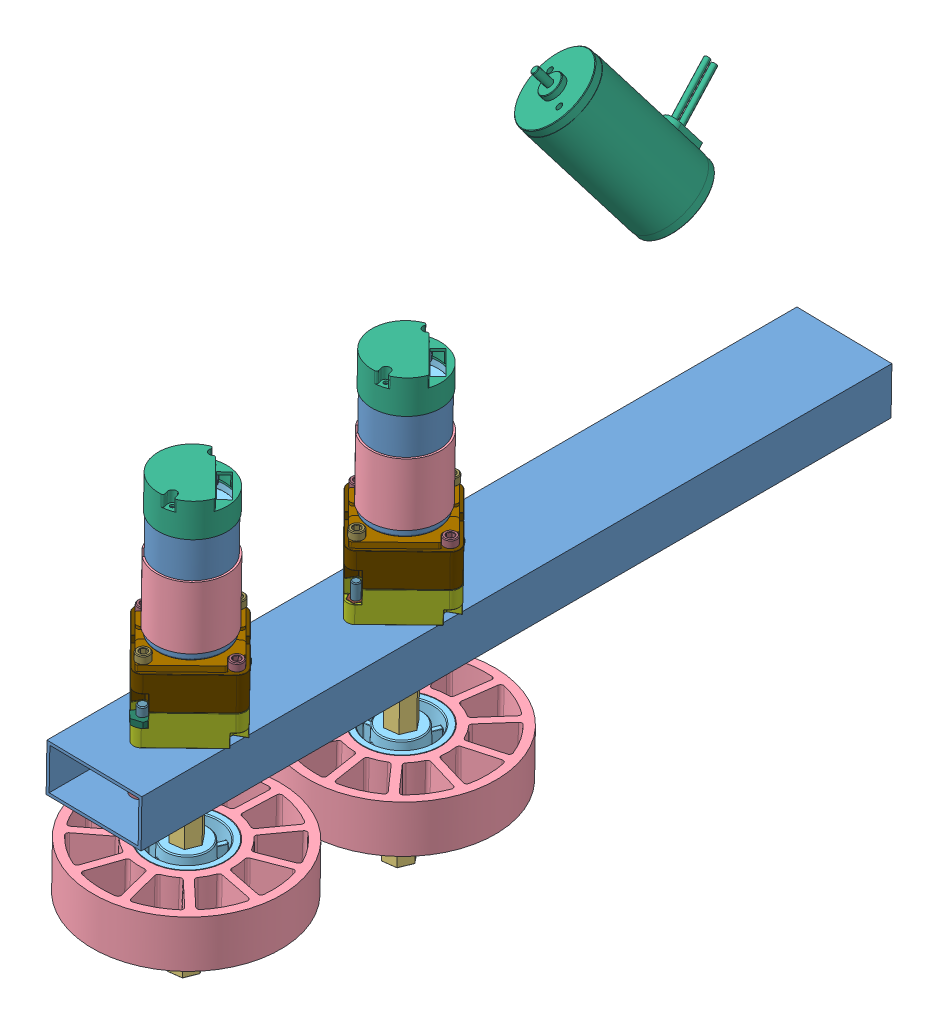
SolidWorks assembly intake final, configuration Default. Lengths in mm.
Overall size (289.95 238.09 525.75).
113 component instances, 33 part files, 37 mates.
Components (placement in the parent):
- 1X2 by 15 inch thin-1: 1X2 by 15 inch thin [Default] at (-67.4663 99.9227 151.2004) x (0.999855 -0.01704 -0.000167) z (0.000167 0.000026 1) size (50.8 25.4 401.32)
- Hex Bearing .5 in internal-4: Hex Bearing .5 in internal [Default] at (-41.9351 105.0953 387.416) x (-0.999854 0.01704 0.001214) z (0.001214 0.000008 0.999999) size (31.12 7.94 31.12)
- Hex shaft 0.5-2: Hex shaft 0.5 [Default] at (-43.6631 0.2077 387.3715) x (-0.623949 0.010611 -0.781393) z (0.01704 0.999855 -0.000029) size (14.66 12.7 127)
- intake wheel-3: intake wheel [Default] at (-59.5152 44.3515 385.9897) x (-0.988582 0.016852 0.149738) z (0.01704 0.999855 -0.000029) size (101.6 101.6 25.74)
  - 4IN Compliant Wheel FINAL Overmold-1: 4IN Compliant Wheel FINAL Overmold [Default] at (-16.2374 3.8509 18.652) size (101.6 101.6 25.74)
  - 2in Wheel Intergrated 0500 HEX Hub-1: 2in Wheel Intergrated 0500 HEX Hub [Default] at (-16.2374 3.8509 5.952) x (-1 0 0) z (0 0 -1) size (41.91 41.91 25.4)
- Hex Bearing .5 in internal-7: Hex Bearing .5 in internal [Default] at (-41.9032 105.8481 501.716) x (-0.079762 0.001388 0.996813) z (0.996668 -0.016983 0.079774) size (31.12 7.94 31.12)
- Hex shaft 0.5-3: Hex shaft 0.5 [Default] at (-41.9272 133.1401 501.7508) x (0.988582 -0.016852 -0.149738) z (-0.01704 -0.999855 0.000029) size (14.66 12.7 127)
- intake wheel-5: intake wheel [Default] at (-50.4764 47.8612 486.6579) x (-0.623949 0.010611 -0.781393) z (0.01704 0.999855 -0.000029) size (101.6 101.6 25.74)
  - 4IN Compliant Wheel FINAL Overmold-1: 4IN Compliant Wheel FINAL Overmold [Default] at (-16.2374 3.8509 18.652) size (101.6 101.6 25.74)
  - 2in Wheel Intergrated 0500 HEX Hub-1: 2in Wheel Intergrated 0500 HEX Hub [Default] at (-16.2374 3.8509 5.952) x (-1 0 0) z (0 0 -1) size (41.91 41.91 25.4)
- Bag CIM-1: Bag CIM [Default] at (-216.6556 141.8279 131.1738) x (0.798694 0.030203 0.600979) z (-0.403164 0.768285 0.49719) size (59.11 59.11 84.5)
- VersaPlanetary_Lite_0_Stage_1_2_Hex_Universal_Female_Output (1)-2: VersaPlanetary_Lite_0_Stage_1_2_Hex_Universal_Female_Output (1) [Default] at (-41.3027 141.0851 501.715) x (0.706859 -0.012067 -0.707252) z (0.01704 0.999855 -0.000029) size (52.33 52.33 132.34)
  - VersaPlanetary Output Blocks_VP Lite Output Block-1: VersaPlanetary Output Blocks_VP Lite Output Block [Default] at origin size (52.33 52.33 18.13)
    - 217-5823-100 Rev1-1: 217-5823-100 Rev1 [Default] at (0 0 6.9329) size (52.33 52.33 18.13)
      - 217-5823-001 Rev7-1: 217-5823-001 Rev7 [Default] at origin size (45.29 45.29 18.13)
      - 217-2742-001 Rev4-1: 217-2742-001 Rev4 [Default] at (0 0 -22.225) x (0 0 1) z (-0.999905 0.013777 0) size (7 28 28)
      - 217-2742-001 Rev4-2: 217-2742-001 Rev4 [Default] at (0 0 -13.9329) x (0 0 1) z (-0.491658 -0.870788 0) size (7 28 28)
      - 217-5823-007 Rev2-1: 217-5823-007 Rev2 [Default] at (-11.3137 11.3137 -14.225) x (0 1 0) z (1 0 0) size (3.5 6.32 3.5)
      - 217-5823-008 Rev3-1: 217-5823-008 Rev3 [Default] at (0 0 -15.225) x (0.707107 0.707107 0) z (0 0 1) size (37 37 1)
      - 217-5823-009 Rev1-1: 217-5823-009 Rev1 [Default] at (-17.4998 17.4998 -12.675) x (0.258819 -0.965926 0) z (-0.965926 -0.258819 0) size (7.33 7.23 6.35)
      - 217-5823-009 Rev1-2: 217-5823-009 Rev1 [Default] at (-17.9605 -17.9605 -16.95) x (0.707107 -0.707107 0) z (-0.707107 -0.707107 0) size (7.33 7.23 6.35)
      - 217-5823-009 Rev1-3: 217-5823-009 Rev1 [Default] at (17.9605 17.9605 -16.95) x (-0.258819 -0.965926 0) z (-0.965926 0.258819 0) size (7.33 7.23 6.35)
      - 217-5823-009 Rev1-4: 217-5823-009 Rev1 [Default] at (17.4998 -17.4998 -12.675) x (0.258819 -0.965926 0) z (-0.965926 -0.258819 0) size (7.33 7.23 6.35)
      - 217-5823-007 Rev2-2: 217-5823-007 Rev2 [Default] at (11.3137 11.3137 -14.225) x (1 0 0) z (0 -1 0) size (3.5 6.32 3.5)
      - 217-5823-007 Rev2-3: 217-5823-007 Rev2 [Default] at (11.3137 -11.3137 -14.225) x (0 -1 0) z (-1 0 0) size (3.5 6.32 3.5)
      - 217-5823-007 Rev2-4: 217-5823-007 Rev2 [Default] at (-11.3137 -11.3137 -14.225) x (-1 0 0) z (0 1 0) size (3.5 6.32 3.5)
      - 217-2625-017 Rev1_9714K61-1: 217-2625-017 Rev1_9714K61 [Default] at (-0.2889 -0.1863 -14.225) x (0.928856 0.370441 0) z (0.370441 -0.928856 0) size (28.51 4.98 30.18)
  - VersaPlanetary Output Shafts_0.500 Hex-1: VersaPlanetary Output Shafts_0.500 Hex [Default] x (-1 0 0) z (0 0 -1) size (22.58 22.1 42.62)
    - 217-5839-000 Rev1_500 Hex-1: 217-5839-000 Rev1_500 Hex [Default] at (0 0 7.6524) x (-1 0 0) z (0 0 1) size (22.58 22.1 42.62)
      - 217-5839-001 Rev6-1: 217-5839-001 Rev6 [Default] at origin size (18 18 32.62)
      - 217-5839-005 Rev1_91251A148-1: 217-5839-005 Rev1_91251A148 [Default] at (0 0 1.5524) x (-0.465417 -0.885092 0) z (0 0 -1) size (5.74 5.74 16.39)
      - 217-5839-006 Rev4-1: 217-5839-006 Rev4 [Default] at (0 0 18.2524) x (0.993768 0.111469 0) z (0 0 1) size (20 20 18)
      - 217-4649-007 Rev1_94105A824-1: 217-4649-007 Rev1_94105A824 [Default] at (9.1095 1.0218 24.0024) x (0.016297 -0.145289 -0.989255) z (0.993768 0.111469 0) size (4.83 4.83 4.9)
  - 217-2625-018 Rev1_98541A410-1: 217-2625-018 Rev1_98541A410 [Default] at (0 0 0.5) x (0 0 1) z (-1 0 0) size (1 19.6 17.4)
  - VersaPlanetary Input Blocks_VP LIte Input Block-1: VersaPlanetary Input Blocks_VP LIte Input Block [Default] at (0 0 0.4329) size (45.6 45.6 18.01)
    - 217-5823-200 Rev1-1: 217-5823-200 Rev1 [Default] at (0 0 10.5) size (45.6 45.6 18.01)
      - 217-5823-002 Rev7-1: 217-5823-002 Rev7 [Default] at origin size (45.31 45.31 18.01)
      - 217-5823-009 Rev1-1: 217-5823-009 Rev1 [Default] at (17.9605 17.9605 1.325) x (0.707107 -0.707107 0) z (-0.707107 -0.707107 0) size (7.33 7.23 6.35)
      - 217-5823-009 Rev1-2: 217-5823-009 Rev1 [Default] at (-17.9605 -17.9605 1.325) x (0.707107 -0.707107 0) z (-0.707107 -0.707107 0) size (7.33 7.23 6.35)
  - VersaPlanetary All Non-CIM Motors_NeveRest Motor-1: VersaPlanetary All Non-CIM Motors_NeveRest Motor [Default] at (0 0 18.4329) size (42 42 92.9)
    - am-3104-1: am-3104 [Default] at (0 0 31.5) x (0 1 0) z (0 0 -1) size (38 37.8 83.6)
      - am-3104-001-1: am-3104-001 [Default] at origin size (36 36 61)
      - am-3104-002-1: am-3104-002 [Default] at (0 0 29.9) size (12 12 4)
      - am-3104-003-1: am-3104-003 [Default] at (0 0 -2.4) size (3.18 3.18 79)
      - am-3104-004-1: am-3104-004 [Default] at (0 0 7.75) size (38 37.8 33.5)
      - am-3104-005-1: am-3104-005 [Default] at (0 0 -32) size (35 35 11)
      - am-3104-006-1: am-3104-006 [Default] at (0 0 -37.5) size (37 37 18)
    - 217-2625-012 Rev1-1: 217-2625-012 Rev1 [Default] at (0 0 -9.5142) size (8.01 7.94 7.5)
    - 217-4649-001 Rev1-1: 217-4649-001 Rev1 [Default] at (0 0 -10.5) x (-0.037394 -0.999301 0) z (0 0 -1) size (18 18 13)
    - 217-4649-007 Rev1_94105A824-1: 217-4649-007 Rev1_94105A824 [Default] at (-6.7787 0.2537 -5.025) x (0.037394 0.999301 0) z (-0.999301 0.037394 0) size (4.83 4.83 4.9)
    - 217-2822-001 Rev4-1: 217-2822-001 Rev4 [Default] at (0 0 1.5) size (42 42 4.8)
    - 217-4649-005 Rev1_SSA0003-008BA-1: 217-4649-005 Rev1_SSA0003-008BA [Default] at (0 -12.5 0) x (0.07598 0.997109 0) z (-0.997109 0.07598 0) size (5.5 11 5.5)
    - 217-4649-005 Rev1_SSA0003-008BA-2: 217-4649-005 Rev1_SSA0003-008BA [Default] at (0 12.5 0) x (0.246835 -0.969058 0) z (0.969058 0.246835 0) size (5.5 11 5.5)
    - 217-4649-006 Rev1_SSA0004-008BA-1: 217-4649-006 Rev1_SSA0004-008BA [Default] at (0 12.5 0) x (1 0 0) z (0 1 0) size (7 14 7)
  - #8-32 SHCS, Grade 8 Steel Rev2_SSA0832-0500ZB-1: #8-32 SHCS, Grade 8 Steel Rev2_SSA0832-0500ZB [Default] at (-17.9605 -17.9605 9.0829) size (6.86 6.86 17.07)
  - #8-32 SHCS, Grade 8 Steel Rev2_SSA0832-0500ZB-2: #8-32 SHCS, Grade 8 Steel Rev2_SSA0832-0500ZB [Default] at (17.9605 17.9605 9.0829) x (-0.997343 -0.072854 0) z (0 0 1) size (6.86 6.86 17.07)
  - #8-32 SHCS, Grade 8 Steel Rev2_SSA0832-1125ZB-1: #8-32 SHCS, Grade 8 Steel Rev2_SSA0832-1125ZB [Default] at (-17.4998 17.4998 -10.1421) size (6.86 6.86 32.95)
  - #8-32 SHCS, Grade 8 Steel Rev2_SSA0832-1125ZB-2: #8-32 SHCS, Grade 8 Steel Rev2_SSA0832-1125ZB [Default] at (17.4998 -17.4998 -10.1421) x (-0.266391 -0.963865 0) z (0 0 1) size (6.86 6.86 32.95)
- socket head cap screw_ai-1: socket head cap screw_ai [HX-SHCS 0.19-32x0.75x0.75-N] at (-41.6827 118.4834 527.1156) x (0.01704 0.999855 -0.000029) z (-0.019413 0.00036 0.999811) size (23.88 7.94 7.94)
- machine screw nut hex_ai-2: machine screw nut hex_ai [MSHXNUT 0.190-24-S-N] at (-41.4141 134.2446 527.1152) x (0.671461 -0.011465 -0.740951) z (-0.01704 -0.999855 0.000029) size (9.53 11 3.3)
- machine screw nut hex_ai-3: machine screw nut hex_ai [MSHXNUT 0.190-24-S-N] at (-41.3682 137.5449 476.3151) x (-0.852765 0.014518 -0.522093) z (0.01704 0.999855 -0.000029) size (9.53 11 3.3)
- socket head cap screw_ai-6: socket head cap screw_ai [HX-SHCS 0.164-36x0.75x0.75-N] at (-41.6818 119.1424 476.3156) x (0.01704 0.999855 -0.000029) z (-0.592394 0.010073 -0.805586) size (23.22 6.86 6.86)
- VersaPlanetary_Lite_0_Stage_1_2_Hex_Universal_Female_Output (1)-3: VersaPlanetary_Lite_0_Stage_1_2_Hex_Universal_Female_Output (1) [Default] at (-41.3218 141.0821 387.415) x (0.706859 -0.012067 -0.707252) z (0.01704 0.999855 -0.000029) size (52.33 52.33 132.34)
  - VersaPlanetary Output Blocks_VP Lite Output Block-1: VersaPlanetary Output Blocks_VP Lite Output Block [Default] at origin size (52.33 52.33 18.13)
    - 217-5823-100 Rev1-1: 217-5823-100 Rev1 [Default] at (0 0 6.9329) size (52.33 52.33 18.13)
      - 217-5823-001 Rev7-1: 217-5823-001 Rev7 [Default] at origin size (45.29 45.29 18.13)
      - 217-2742-001 Rev4-1: 217-2742-001 Rev4 [Default] at (0 0 -22.225) x (0 0 1) z (-0.999905 0.013777 0) size (7 28 28)
      - 217-2742-001 Rev4-2: 217-2742-001 Rev4 [Default] at (0 0 -13.9329) x (0 0 1) z (-0.491658 -0.870788 0) size (7 28 28)
      - 217-5823-007 Rev2-1: 217-5823-007 Rev2 [Default] at (-11.3137 11.3137 -14.225) x (0 1 0) z (1 0 0) size (3.5 6.32 3.5)
      - 217-5823-008 Rev3-1: 217-5823-008 Rev3 [Default] at (0 0 -15.225) x (0.707107 0.707107 0) z (0 0 1) size (37 37 1)
      - 217-5823-009 Rev1-1: 217-5823-009 Rev1 [Default] at (-17.4998 17.4998 -12.675) x (0.258819 -0.965926 0) z (-0.965926 -0.258819 0) size (7.33 7.23 6.35)
      - 217-5823-009 Rev1-2: 217-5823-009 Rev1 [Default] at (-17.9605 -17.9605 -16.95) x (0.707107 -0.707107 0) z (-0.707107 -0.707107 0) size (7.33 7.23 6.35)
      - 217-5823-009 Rev1-3: 217-5823-009 Rev1 [Default] at (17.9605 17.9605 -16.95) x (-0.258819 -0.965926 0) z (-0.965926 0.258819 0) size (7.33 7.23 6.35)
      - 217-5823-009 Rev1-4: 217-5823-009 Rev1 [Default] at (17.4998 -17.4998 -12.675) x (0.258819 -0.965926 0) z (-0.965926 -0.258819 0) size (7.33 7.23 6.35)
      - 217-5823-007 Rev2-2: 217-5823-007 Rev2 [Default] at (11.3137 11.3137 -14.225) x (1 0 0) z (0 -1 0) size (3.5 6.32 3.5)
      - 217-5823-007 Rev2-3: 217-5823-007 Rev2 [Default] at (11.3137 -11.3137 -14.225) x (0 -1 0) z (-1 0 0) size (3.5 6.32 3.5)
      - 217-5823-007 Rev2-4: 217-5823-007 Rev2 [Default] at (-11.3137 -11.3137 -14.225) x (-1 0 0) z (0 1 0) size (3.5 6.32 3.5)
      - 217-2625-017 Rev1_9714K61-1: 217-2625-017 Rev1_9714K61 [Default] at (-0.2889 -0.1863 -14.225) x (0.928856 0.370441 0) z (0.370441 -0.928856 0) size (28.51 4.98 30.18)
  - VersaPlanetary Output Shafts_0.500 Hex-1: VersaPlanetary Output Shafts_0.500 Hex [Default] x (-1 0 0) z (0 0 -1) size (22.58 22.1 42.62)
    - 217-5839-000 Rev1_500 Hex-1: 217-5839-000 Rev1_500 Hex [Default] at (0 0 7.6524) x (-1 0 0) z (0 0 1) size (22.58 22.1 42.62)
      - 217-5839-001 Rev6-1: 217-5839-001 Rev6 [Default] at origin size (18 18 32.62)
      - 217-5839-005 Rev1_91251A148-1: 217-5839-005 Rev1_91251A148 [Default] at (0 0 1.5524) x (-0.465417 -0.885092 0) z (0 0 -1) size (5.74 5.74 16.39)
      - 217-5839-006 Rev4-1: 217-5839-006 Rev4 [Default] at (0 0 18.2524) x (0.993768 0.111469 0) z (0 0 1) size (20 20 18)
      - 217-4649-007 Rev1_94105A824-1: 217-4649-007 Rev1_94105A824 [Default] at (9.1095 1.0218 24.0024) x (0.016297 -0.145289 -0.989255) z (0.993768 0.111469 0) size (4.83 4.83 4.9)
  - 217-2625-018 Rev1_98541A410-1: 217-2625-018 Rev1_98541A410 [Default] at (0 0 0.5) x (0 0 1) z (-1 0 0) size (1 19.6 17.4)
  - VersaPlanetary Input Blocks_VP LIte Input Block-1: VersaPlanetary Input Blocks_VP LIte Input Block [Default] at (0 0 0.4329) size (45.6 45.6 18.01)
    - 217-5823-200 Rev1-1: 217-5823-200 Rev1 [Default] at (0 0 10.5) size (45.6 45.6 18.01)
      - 217-5823-002 Rev7-1: 217-5823-002 Rev7 [Default] at origin size (45.31 45.31 18.01)
      - 217-5823-009 Rev1-1: 217-5823-009 Rev1 [Default] at (17.9605 17.9605 1.325) x (0.707107 -0.707107 0) z (-0.707107 -0.707107 0) size (7.33 7.23 6.35)
      - 217-5823-009 Rev1-2: 217-5823-009 Rev1 [Default] at (-17.9605 -17.9605 1.325) x (0.707107 -0.707107 0) z (-0.707107 -0.707107 0) size (7.33 7.23 6.35)
  - VersaPlanetary All Non-CIM Motors_NeveRest Motor-1: VersaPlanetary All Non-CIM Motors_NeveRest Motor [Default] at (0 0 18.4329) size (42 42 92.9)
    - am-3104-1: am-3104 [Default] at (0 0 31.5) x (0 1 0) z (0 0 -1) size (38 37.8 83.6)
      - am-3104-001-1: am-3104-001 [Default] at origin size (36 36 61)
      - am-3104-002-1: am-3104-002 [Default] at (0 0 29.9) size (12 12 4)
      - am-3104-003-1: am-3104-003 [Default] at (0 0 -2.4) size (3.18 3.18 79)
      - am-3104-004-1: am-3104-004 [Default] at (0 0 7.75) size (38 37.8 33.5)
      - am-3104-005-1: am-3104-005 [Default] at (0 0 -32) size (35 35 11)
      - am-3104-006-1: am-3104-006 [Default] at (0 0 -37.5) size (37 37 18)
    - 217-2625-012 Rev1-1: 217-2625-012 Rev1 [Default] at (0 0 -9.5142) size (8.01 7.94 7.5)
    - 217-4649-001 Rev1-1: 217-4649-001 Rev1 [Default] at (0 0 -10.5) x (-0.037394 -0.999301 0) z (0 0 -1) size (18 18 13)
    - 217-4649-007 Rev1_94105A824-1: 217-4649-007 Rev1_94105A824 [Default] at (-6.7787 0.2537 -5.025) x (0.037394 0.999301 0) z (-0.999301 0.037394 0) size (4.83 4.83 4.9)
    - 217-2822-001 Rev4-1: 217-2822-001 Rev4 [Default] at (0 0 1.5) size (42 42 4.8)
    - 217-4649-005 Rev1_SSA0003-008BA-1: 217-4649-005 Rev1_SSA0003-008BA [Default] at (0 -12.5 0) x (0.07598 0.997109 0) z (-0.997109 0.07598 0) size (5.5 11 5.5)
    - 217-4649-005 Rev1_SSA0003-008BA-2: 217-4649-005 Rev1_SSA0003-008BA [Default] at (0 12.5 0) x (0.246835 -0.969058 0) z (0.969058 0.246835 0) size (5.5 11 5.5)
    - 217-4649-006 Rev1_SSA0004-008BA-1: 217-4649-006 Rev1_SSA0004-008BA [Default] at (0 12.5 0) x (1 0 0) z (0 1 0) size (7 14 7)
  - #8-32 SHCS, Grade 8 Steel Rev2_SSA0832-0500ZB-1: #8-32 SHCS, Grade 8 Steel Rev2_SSA0832-0500ZB [Default] at (-17.9605 -17.9605 9.0829) size (6.86 6.86 17.07)
  - #8-32 SHCS, Grade 8 Steel Rev2_SSA0832-0500ZB-2: #8-32 SHCS, Grade 8 Steel Rev2_SSA0832-0500ZB [Default] at (17.9605 17.9605 9.0829) x (-0.997343 -0.072854 0) z (0 0 1) size (6.86 6.86 17.07)
  - #8-32 SHCS, Grade 8 Steel Rev2_SSA0832-1125ZB-1: #8-32 SHCS, Grade 8 Steel Rev2_SSA0832-1125ZB [Default] at (-17.4998 17.4998 -10.1421) size (6.86 6.86 32.95)
  - #8-32 SHCS, Grade 8 Steel Rev2_SSA0832-1125ZB-2: #8-32 SHCS, Grade 8 Steel Rev2_SSA0832-1125ZB [Default] at (17.4998 -17.4998 -10.1421) x (-0.266391 -0.963865 0) z (0 0 1) size (6.86 6.86 32.95)
- socket head cap screw_ai-7: socket head cap screw_ai [HX-SHCS 0.164-36x0.75x0.75-N] at (-41.7009 119.1395 362.0156) x (0.01704 0.999855 -0.000029) z (0.000029 0.000028 1) size (23.22 6.86 6.86)
- socket head cap screw_ai-8: socket head cap screw_ai [HX-SHCS 0.164-36x0.75x0.75-N] at (-41.6905 119.1408 412.8156) x (0.01704 0.999855 -0.000029) z (0.000029 0.000028 1) size (23.22 6.86 6.86)
- machine screw nut hex_ai-4: machine screw nut hex_ai [MSHXNUT 0.190-24-S-N] at (-41.3873 137.5419 362.0151) x (-0.490899 0.008341 -0.871176) z (0.01704 0.999855 -0.000029) size (9.53 11 3.3)
Mates (geometry in assembly coordinates):
- Concentric7: concentric anti-aligned: cylinder of 1X2 by 15 inch thin-1 through (-41.641 122.3527 387.4155) axis (0.01704 0.999855 -0.000029) radius 10.795; cylinder of Hex Bearing .5 in internal-4 through (-41.9351 105.0953 387.416) axis (-0.01704 -0.999855 0.000029) radius 14.2748
- Coincident5: coincident aligned: plane of 1X2 by 15 inch thin-1 through (-67.3992 99.9332 552.5204) normal (-0.01704 -0.999855 0.000029); circle of Hex Bearing .5 in internal-4
- Coincident14: coincident anti-aligned: plane of Hex shaft 0.5-2 through (-50.9117 0.3313 388.4694) normal (-0.781279 0.013333 0.62404); plane of intake wheel-3/2in Wheel Intergrated 0500 HEX Hub-1 through (-50.2792 37.4452 388.4684) normal (0.781279 -0.013333 -0.62404)
- Parallel4: parallel anti-aligned: plane of 1X2 by 15 inch thin-1 through (-67.3992 99.9332 552.5204) normal (-0.01704 -0.999855 0.000029); plane of intake wheel-3/2in Wheel Intergrated 0500 HEX Hub-1 through (-42.1885 62.711 389.8767) normal (0.01704 0.999855 -0.000029)
- Coincident16: coincident anti-aligned: plane of Hex shaft 0.5-2 through (-48.2381 0.2855 381.6421) normal (-0.930995 0.015856 -0.364686); plane of intake wheel-3/2in Wheel Intergrated 0500 HEX Hub-1 through (-47.5949 37.3992 381.6137) normal (0.930995 -0.015856 0.364686)
- Concentric10: concentric anti-aligned: cylinder of 1X2 by 15 inch thin-1 through (-41.6624 119.9761 501.7156) axis (0.01704 0.999855 -0.000029) radius 10.795; cylinder of Hex Bearing .5 in internal-7 through (-41.9032 105.8481 501.716) axis (-0.01704 -0.999855 0.000029) radius 14.2748
- Coincident25: coincident aligned: plane of 1X2 by 15 inch thin-1 through (-67.3992 99.9332 552.5204) normal (-0.01704 -0.999855 0.000029); circle of Hex Bearing .5 in internal-7
- Coincident29: coincident anti-aligned: plane of Hex shaft 0.5-3 through (-44.6008 133.1859 508.5781) normal (-0.781279 0.013333 0.62404); plane of intake wheel-5/2in Wheel Intergrated 0500 HEX Hub-1 through (-50.7463 41.1173 502.8514) normal (0.781279 -0.013333 -0.62404)
- Parallel9: parallel anti-aligned: plane of 1X2 by 15 inch thin-1 through (-67.3992 99.9332 552.5204) normal (-0.01704 -0.999855 0.000029); plane of intake wheel-5/2in Wheel Intergrated 0500 HEX Hub-1 through (-45.0203 66.4234 503.3334) normal (0.01704 0.999855 -0.000029)
- Coincident31: coincident anti-aligned: plane of Hex shaft 0.5-3 through (-49.1759 133.2637 502.8487) normal (-0.930995 0.015856 -0.364686); plane of intake wheel-5/2in Wheel Intergrated 0500 HEX Hub-1 through (-48.062 41.0714 495.9967) normal (0.930995 -0.015856 0.364686)
- Parallel10: parallel anti-aligned: plane of 1X2 by 15 inch thin-1 through (-66.9664 125.3295 552.5197) normal (0.01704 0.999855 -0.000029); plane of VersaPlanetary_Lite_0_Stage_1_2_Hex_Universal_Female_Output (1)-2/VersaPlanetary Output Shafts_0.500 Hex-1/217-5839-000 Rev1_500 Hex-1/217-5839-006 Rev4-1 through (-41.9145 105.1855 501.716) normal (-0.01704 -0.999855 0.000029)
- Coincident33: coincident anti-aligned: plane of Hex shaft 0.5-3 through (-49.1759 133.2637 502.8487) normal (-0.930995 0.015856 -0.364686); moEndPointRef_w of VersaPlanetary_Lite_0_Stage_1_2_Hex_Universal_Female_Output (1)-2/VersaPlanetary Output Shafts_0.500 Hex-1/217-5839-000 Rev1_500 Hex-1/217-5839-001 Rev6-1
- Coincident34: coincident anti-aligned: plane of Hex shaft 0.5-3 through (-46.5022 133.2179 496.0213) normal (-0.149716 0.002523 -0.988726); plane of VersaPlanetary_Lite_0_Stage_1_2_Hex_Universal_Female_Output (1)-2/VersaPlanetary Output Shafts_0.500 Hex-1/217-5839-000 Rev1_500 Hex-1/217-5839-006 Rev4-1 through (-46.014 134.7755 495.9514) normal (0.149716 -0.002523 0.988726)
- Coincident35: coincident anti-aligned: plane of 1X2 by 15 inch thin-1 through (-66.9664 125.3295 552.5197) normal (0.01704 0.999855 -0.000029); plane of VersaPlanetary_Lite_0_Stage_1_2_Hex_Universal_Female_Output (1)-2/VersaPlanetary Output Blocks_VP Lite Output Block-1/217-5823-100 Rev1-1/217-5823-001 Rev7-1 through (-73.5529 125.4403 501.722) normal (-0.01704 -0.999855 0.000029)
- Angle1: planar angle = 2.356194 rad anti-aligned: plane of VersaPlanetary_Lite_0_Stage_1_2_Hex_Universal_Female_Output (1)-2/VersaPlanetary Output Blocks_VP Lite Output Block-1/217-5823-100 Rev1-1/217-5823-001 Rev7-1 through (-41.6516 124.8975 533.6148) normal (0.706974 -0.020756 0.706935); plane of 1X2 by 15 inch thin-1 through (-16.6066 99.0676 552.512) normal (0.999855 -0.01704 -0.000167)
- Concentric11: concentric anti-aligned: cylinder of 1X2 by 15 inch thin-1 through (-41.6624 119.9761 501.7156) axis (0.01704 0.999855 -0.000029) radius 10.795; cylinder of VersaPlanetary_Lite_0_Stage_1_2_Hex_Universal_Female_Output (1)-2/VersaPlanetary Output Shafts_0.500 Hex-1/217-5839-000 Rev1_500 Hex-1/217-5839-001 Rev6-1 through (8478.5848 500060.8376 487.2597) axis (-0.01704 -0.999855 0.000029) radius 9
- Concentric12: concentric anti-aligned: cylinder of VersaPlanetary_Lite_0_Stage_1_2_Hex_Universal_Female_Output (1)-2/VersaPlanetary Output Blocks_VP Lite Output Block-1/217-5823-100 Rev1-1/217-5823-009 Rev1-2 through (-41.5223 127.8956 527.1154) axis (0.01704 0.999855 -0.000029) radius 2.0955; cylinder of socket head cap screw_ai-1 through (-42.2237 86.738 527.1166) axis (-0.01704 -0.999855 0.000029) radius 2.413
- Coincident38: coincident anti-aligned: plane of 1X2 by 15 inch thin-1 through (-65.4062 123.7152 552.5195) normal (-0.01704 -0.999855 0.000029); plane of socket head cap screw_ai-1 through (-45.5679 123.3763 527.0384) normal (0.01704 0.999855 -0.000029)
- Concentric14: concentric aligned: cylinder of socket head cap screw_ai-1 through (-42.2237 86.738 527.1166) axis (-0.01704 -0.999855 0.000029) radius 2.413; cylinder of machine screw nut hex_ai-2 through (-41.3578 137.5462 527.1151) axis (-0.01704 -0.999855 0.000029) radius 1.8986
- Coincident39: coincident anti-aligned: plane of VersaPlanetary_Lite_0_Stage_1_2_Hex_Universal_Female_Output (1)-2/VersaPlanetary Output Blocks_VP Lite Output Block-1/217-5823-100 Rev1-1/217-5823-009 Rev1-2 through (-43.2475 134.2758 523.9406) normal (0.01704 0.999855 -0.000029); plane of machine screw nut hex_ai-2 through (-47.8097 134.3538 534.1728) normal (-0.01704 -0.999855 0.000029)
- Concentric21: concentric anti-aligned: cylinder of VersaPlanetary_Lite_0_Stage_1_2_Hex_Universal_Female_Output (1)-2/VersaPlanetary Output Blocks_VP Lite Output Block-1/217-5823-100 Rev1-1/217-5823-009 Rev1-3 through (-41.5327 127.8943 476.3154) axis (0.01704 0.999855 -0.000029) radius 2.0955; cylinder of socket head cap screw_ai-6 through (-42.2229 87.3971 476.3165) axis (-0.01704 -0.999855 0.000029) radius 2.0828
- Coincident43: coincident aligned: plane of 1X2 by 15 inch thin-1 through (-65.4062 123.7152 552.5195) normal (-0.01704 -0.999855 0.000029); circle of socket head cap screw_ai-6
- Concentric22: concentric anti-aligned: cylinder of machine screw nut hex_ai-3 through (-41.4245 134.2434 476.3152) axis (0.01704 0.999855 -0.000029) radius 1.8986; cylinder of socket head cap screw_ai-6 through (-42.2229 87.3971 476.3165) axis (-0.01704 -0.999855 0.000029) radius 2.0828
- Coincident48: coincident anti-aligned: plane of VersaPlanetary_Lite_0_Stage_1_2_Hex_Universal_Female_Output (1)-2/VersaPlanetary Output Blocks_VP Lite Output Block-1/217-5823-100 Rev1-1/217-5823-009 Rev1-3 through (-39.5923 134.212 473.1398) normal (0.01704 0.999855 -0.000029); plane of machine screw nut hex_ai-3 through (-33.3019 134.1051 481.2881) normal (-0.01704 -0.999855 0.000029)
- Coincident49: coincident anti-aligned: plane of Hex shaft 0.5-2 through (-40.9895 0.1619 380.5441) normal (-0.149716 0.002523 -0.988726); plane of VersaPlanetary_Lite_0_Stage_1_2_Hex_Universal_Female_Output (1)-3/VersaPlanetary Output Shafts_0.500 Hex-1/217-5839-000 Rev1_500 Hex-1/217-5839-006 Rev4-1 through (-46.0331 134.7725 381.6514) normal (0.149716 -0.002523 0.988726)
- Parallel15: parallel anti-aligned: plane of 1X2 by 15 inch thin-1 through (-66.9664 125.3295 552.5197) normal (0.01704 0.999855 -0.000029); plane of VersaPlanetary_Lite_0_Stage_1_2_Hex_Universal_Female_Output (1)-3/VersaPlanetary Output Shafts_0.500 Hex-1/217-5839-000 Rev1_500 Hex-1/217-5839-006 Rev4-1 through (-41.9336 105.1825 387.416) normal (-0.01704 -0.999855 0.000029)
- Coincident54: coincident anti-aligned: plane of Hex shaft 0.5-2 through (-39.0881 0.1299 393.101) normal (0.930995 -0.015856 0.364686); plane of VersaPlanetary_Lite_0_Stage_1_2_Hex_Universal_Female_Output (1)-3/VersaPlanetary Output Shafts_0.500 Hex-1/217-5839-000 Rev1_500 Hex-1/217-5839-006 Rev4-1 through (-34.1385 134.5699 386.3107) normal (-0.930995 0.015856 -0.364686)
- Coincident55: coincident anti-aligned: plane of 1X2 by 15 inch thin-1 through (-66.9664 125.3295 552.5197) normal (0.01704 0.999855 -0.000029); plane of VersaPlanetary_Lite_0_Stage_1_2_Hex_Universal_Female_Output (1)-3/VersaPlanetary Output Blocks_VP Lite Output Block-1/217-5823-100 Rev1-1/217-5823-001 Rev7-1 through (-73.572 125.4373 387.422) normal (-0.01704 -0.999855 0.000029)
- Angle2: planar angle = 2.356194 rad aligned: plane of VersaPlanetary_Lite_0_Stage_1_2_Hex_Universal_Female_Output (1)-3/VersaPlanetary Output Blocks_VP Lite Output Block-1/217-5823-100 Rev1-1/217-5823-001 Rev7-1 through (-73.4924 125.4359 387.5015) normal (-0.707271 0.003305 -0.706935); plane of 1X2 by 15 inch thin-1 through (-16.6066 99.0676 552.512) normal (0.999855 -0.01704 -0.000167)
- Concentric23: concentric anti-aligned: cylinder of 1X2 by 15 inch thin-1 through (-41.641 122.3527 387.4155) axis (0.01704 0.999855 -0.000029) radius 10.795; cylinder of VersaPlanetary_Lite_0_Stage_1_2_Hex_Universal_Female_Output (1)-3/VersaPlanetary Output Shafts_0.500 Hex-1/217-5839-000 Rev1_500 Hex-1/217-5839-001 Rev6-1 through (8478.5657 500060.8347 372.9597) axis (-0.01704 -0.999855 0.000029) radius 9
- Concentric24: concentric anti-aligned: cylinder of VersaPlanetary_Lite_0_Stage_1_2_Hex_Universal_Female_Output (1)-3/VersaPlanetary Output Blocks_VP Lite Output Block-1/217-5823-100 Rev1-1/217-5823-009 Rev1-3 through (-41.5518 127.8913 362.0154) axis (0.01704 0.999855 -0.000029) radius 2.0955; cylinder of socket head cap screw_ai-7 through (-42.242 87.3941 362.0165) axis (-0.01704 -0.999855 0.000029) radius 2.0828
- Coincident58: coincident aligned: plane of 1X2 by 15 inch thin-1 through (-65.4062 123.7152 552.5195) normal (-0.01704 -0.999855 0.000029); circle of socket head cap screw_ai-7
- Concentric25: concentric anti-aligned: cylinder of VersaPlanetary_Lite_0_Stage_1_2_Hex_Universal_Female_Output (1)-3/VersaPlanetary Output Blocks_VP Lite Output Block-1/217-5823-100 Rev1-1/217-5823-009 Rev1-2 through (-41.5414 127.8926 412.8154) axis (0.01704 0.999855 -0.000029) radius 2.0955; cylinder of socket head cap screw_ai-8 through (-42.2315 87.3954 412.8165) axis (-0.01704 -0.999855 0.000029) radius 2.0828
- Coincident59: coincident aligned: plane of 1X2 by 15 inch thin-1 through (-65.4062 123.7152 552.5195) normal (-0.01704 -0.999855 0.000029); circle of socket head cap screw_ai-8
- Parallel21: parallel anti-aligned: plane of 1X2 by 15 inch thin-1 through (-66.9664 125.3295 552.5197) normal (0.01704 0.999855 -0.000029); plane of machine screw nut hex_ai-4 through (-36.7678 134.1609 370.3131) normal (-0.01704 -0.999855 0.000029)
- Concentric27: concentric anti-aligned: cylinder of socket head cap screw_ai-7 through (-42.242 87.3941 362.0165) axis (-0.01704 -0.999855 0.000029) radius 2.0828; cylinder of machine screw nut hex_ai-4 through (-41.4436 134.2404 362.0152) axis (0.01704 0.999855 -0.000029) radius 1.8986
- Coincident63: coincident anti-aligned: plane of VersaPlanetary_Lite_0_Stage_1_2_Hex_Universal_Female_Output (1)-3/VersaPlanetary Output Blocks_VP Lite Output Block-1/217-5823-100 Rev1-1/217-5823-009 Rev1-3 through (-39.6114 134.2091 358.8398) normal (0.01704 0.999855 -0.000029); plane of machine screw nut hex_ai-4 through (-36.7678 134.1609 370.3131) normal (-0.01704 -0.999855 0.000029)
